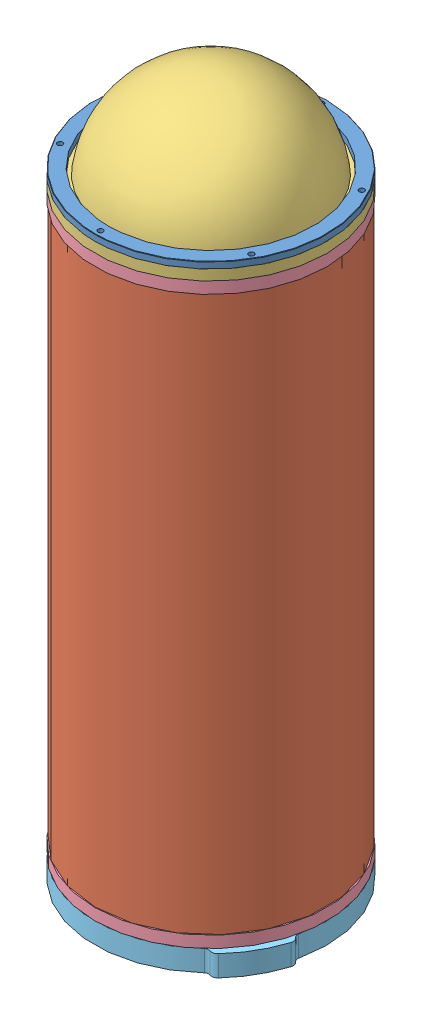
SolidWorks assembly asm_v1, configuration Default. Lengths in mm.
Overall size (156.14 332.25 153.95).
6 component instances, 5 part files, 11 mates.
Components (placement in the parent):
- cap_v1-1: cap_v1 [Default] at (26.4191 61.9197 88.7329) size (110.5 3 110.5)
- tube_v1-1: tube_v1 [Default] at (26.4191 -212.5803 88.7329) size (110 264 110)
- dome_v1-1: dome_v1 [Default] at (26.4191 56.9197 88.7329) x (0 -1 0) z (-0.5 0 0.866025) size (47.25 110.5 110.5)
- flange_seal_v1-1: flange_seal_v1 [Default] at (26.4191 -20.7613 88.7329) x (0 -1 0) z (-0.5 0 0.866025) size (28.5 110.5 110.5)
- flange_seal_v1-2: flange_seal_v1 [Default] at (26.4191 -140.3994 88.7329) x (0 1 0) z (0 0 1) size (28.5 110.5 110.5)
- cap_2_v1-1: cap_2_v1 [Default] at (26.4191 -228.0803 88.7329) x (0.866025 0 0.5) z (-0.5 0 0.866025) size (116.5 10 110.5)
Mates (geometry in assembly coordinates):
- 重合4: coincident aligned: circle of dome_v1-1; circle of flange_seal_v1-1
- 重合5: coincident anti-aligned: circle of cap_v1-1; circle of dome_v1-1
- 同心3: concentric aligned: circle of cap_v1-1; circle of dome_v1-1
- 同心4: concentric aligned: circle of dome_v1-1; circle of flange_seal_v1-1
- 同心6: concentric anti-aligned: circle of tube_v1-1; circle of flange_seal_v1-1
- 距离2: distance = 0 mm anti-aligned: plane of flange_seal_v1-1 through (54.0441 51.4197 40.8849) normal (0 -1 0); plane of tube_v1-1 through (26.4191 51.4197 88.7329) normal (0 1 0)
- 同心7: concentric aligned: circle of tube_v1-1; circle of flange_seal_v1-2
- 距离3: distance = 0 mm anti-aligned: plane of tube_v1-1 through (26.4191 -212.5803 88.7329) normal (0 -1 0); plane of flange_seal_v1-2 through (26.4191 -212.5803 33.4829) normal (0 1 0)
- 同心8: concentric anti-aligned: circle of flange_seal_v1-2; circle of cap_2_v1-1
- 同心9: concentric aligned: circle of flange_seal_v1-2; circle of cap_2_v1-1
- 距离4: distance = 0 mm anti-aligned: plane of cap_2_v1-1 through (26.4191 -218.0803 88.7329) normal (0 1 0); plane of flange_seal_v1-2 through (26.4191 -218.0803 38.9329) normal (0 -1 0)
